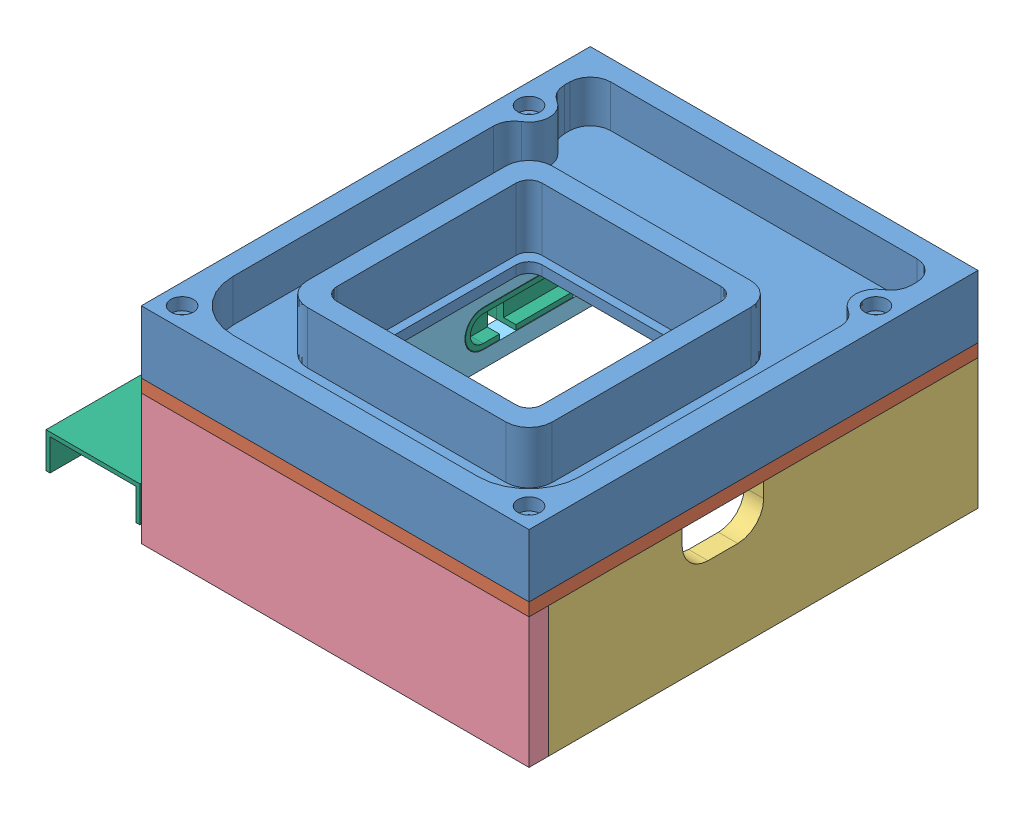
SolidWorks assembly Complete Box, configuration Default. Lengths in mm.
Overall size (236 105.94 220.7).
6 component instances, 6 part files, 15 mates.
Components (placement in the parent):
- Build box Top-1: Build box Top [Default] at origin size (190 35.69 220)
- Build box middle-1: Build box middle [Default] at (0 0 -15) x (1 0 0) z (0 -1 0) size (190 220 6.35)
- wall-2: wall [Default] at (90.2375 -6.35 -19.7625) x (0 0 -1) z (0 -1 0) size (210.47 9.53 63.9)
- wall2-1: wall2 [Default] at (0 -38.3 85.475) size (190 63.9 9.53)
- Wall H-1: Wall H [Default] at (-90.2375 -6.35 -19.7625) x (0 0 -1) z (0 -1 0) size (210.47 9.53 63.9)
- cables-1: cables [Default] at (-95 -53.25 -94) x (0 0 -1) z (1 0 0) size (220.7 17.46 55.53)
Mates (geometry in assembly coordinates):
- Coincident3: coincident anti-aligned: plane of Build box Top-1 through (0 0 0) normal (0 -1 0); plane of Build box middle-1 through (0 0 -15) normal (0 1 0)
- Concentric5: concentric aligned: cylinder of Build box Top-1 through (85 22 85) axis (0 -1 0) radius 5.5565; cylinder of Build box middle-1 through (85 -6.35 85) axis (0 -1 0) radius 3.3
- Concentric6: concentric aligned: cylinder of Build box Top-1 through (-85 22 -85) axis (0 -1 0) radius 5.5565; cylinder of Build box middle-1 through (-85 -6.35 -85) axis (0 -1 0) radius 3.3
- Coincident11: coincident anti-aligned: plane of Build box middle-1 through (0 -6.35 -15) normal (0 -1 0); plane of wall-2 through (90.2375 -6.35 -19.7625) normal (0 1 0)
- Coincident12: coincident aligned: plane of Build box Top-1 through (95 10 0) normal (1 0 0); plane of wall-2 through (95 -70.25 85.475) normal (1 0 0)
- Coincident13: coincident aligned: plane of Build box Top-1 through (0 10 -125) normal (0 0 -1); plane of wall-2 through (95 -70.25 -125) normal (0 0 -1)
- Coincident14: coincident anti-aligned: plane of Build box middle-1 through (0 -6.35 -15) normal (0 -1 0); plane of wall2-1 through (-95 -6.35 95) normal (0 1 0)
- Coincident15: coincident aligned: plane of wall-2 through (95 -70.25 85.475) normal (1 0 0); plane of wall2-1 through (95 -6.35 95) normal (1 0 0)
- Coincident16: coincident aligned: plane of Build box Top-1 through (0 10 95) normal (0 0 1); plane of wall2-1 through (0 -38.3 95) normal (0 0 1)
- Coincident24: coincident aligned: plane of Build box Top-1 through (-95 10 0) normal (-1 0 0); plane of Wall H-1 through (-95 -70.25 85.475) normal (-1 0 0)
- Coincident25: coincident anti-aligned: plane of Build box middle-1 through (0 -6.35 -15) normal (0 -1 0); plane of Wall H-1 through (-90.2375 -6.35 -19.7625) normal (0 1 0)
- Coincident26: coincident anti-aligned: plane of wall2-1 through (0 -38.3 85.475) normal (0 0 -1); plane of Wall H-1 through (-85.475 -70.25 85.475) normal (0 0 1)
- Concentric7: concentric anti-aligned: cylinder of Wall H-1 through (-95 -53.25 -63) axis (1 0 0) radius 9; cylinder of 2-1 through (-85.475 -53.25 -63) axis (-1 0 0) radius 8.7
- Parallel4: parallel anti-aligned: plane of Wall H-1 through (-95 -62.25 -63) normal (0 1 0); plane of 2-1 through (-85.475 -61.95 -115) normal (0 -1 0)
- Coincident31: coincident aligned: plane of Wall H-1 through (-85.475 -70.25 85.475) normal (1 0 0); plane of 2-1 through (-85.475 -53.25 -63) normal (1 0 0)
